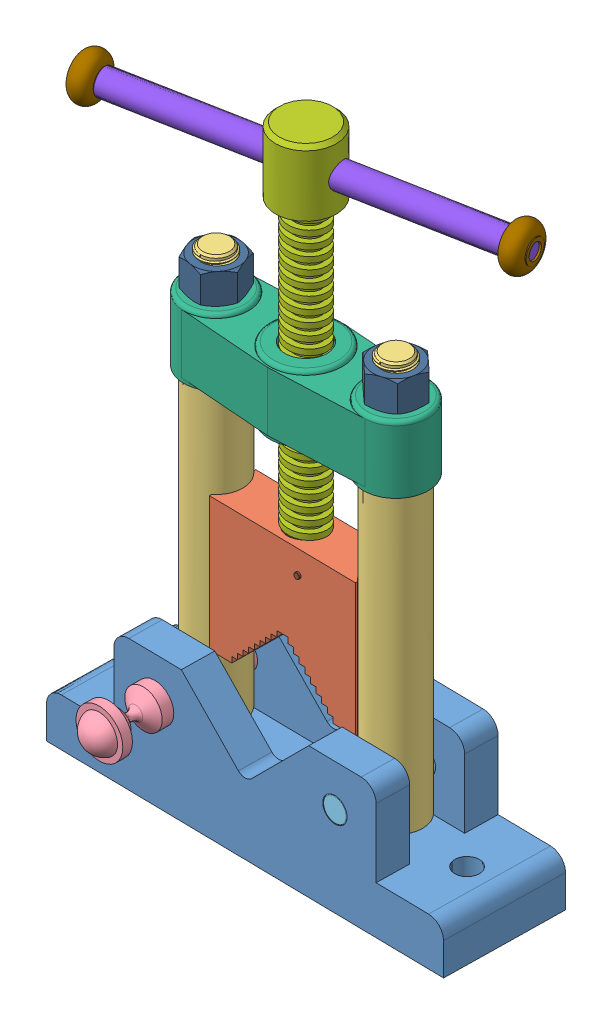
SolidWorks assembly Assem, configuration Default. Lengths in mm.
Overall size (213.02 319.89 110.24).
15 component instances, 11 part files, 36 mates.
Components (placement in the parent):
- Fixed jaw-1: Fixed jaw [Default] at (0.0506 112.578 -0.7967) x (0.999862 0 0.016599) z (-0.016599 0 0.999862) size (212 69 63)
- Movable jaw-1: Movable jaw [Default] at (-0.1493 248.4649 -0.8001) x (0.999862 0 0.016599) z (-0.016599 0 0.999862) size (78 70.54 24)
- Mounting shaft-1: Mounting shaft [Default] at (48.044 276.3556 0) x (0 1 0) z (-0.016599 0 0.999862) size (215.03 28 28)
- Mounting shaft-12: Mounting shaft [Default] at (-47.9428 276.3556 -1.5935) x (0 1 0) z (-0.016599 0 0.999862) size (215.03 28 28)
- Moving pin-1: Moving pin [Default] at (-48.3734 159.578 24.3472) x (0.016599 0 -0.999862) z (0.981424 -0.191161 0.016293) size (109.77 25 25)
- Mounting pin-1: Mounting pin [Default] at (48.5669 159.578 -31.4957) x (0.999862 0.000072 0.016599) z (0.000072 -1 0.000001) size (13 63 13)
- Connecting wedge-1: Connecting wedge [Default] at (0.0506 315.1075 -0.7967) x (0.999862 0 0.016599) z (-0.016599 0 0.999862) size (130 36.3 39.81)
- Spindle screw-1: Spindle screw [Default] at (0.0506 378.2572 -0.7967) x (0 -1 0) z (-0.982605 0 0.18571) size (214 32 32)
- Turning Shaft-1: Turning Shaft [Default] at (45.5082 414.4649 -9.3881) x (0.982605 0 -0.18571) z (0.17415 0.347303 0.92144) size (204 13 13)
- Knob-1: Knob [Default] at (-95.262 414.4649 17.2172) x (-0.129878 -0.71477 -0.687194) z (0.982605 0 -0.18571) size (23.16 23.16 12)
- Knob-2: Knob [Default] at (95.3633 414.4649 -18.8107) x (-0.161669 -0.492095 -0.855398) z (0.982605 0 -0.18571) size (23.16 23.16 12)
- hex nut gradec_iso-2: hex nut gradec_iso [ISO - 4034 - M16 - N] at (48.044 348.5075 0) x (-0.977063 0 -0.212949) z (0 1 0) size (24 27.71 15.9)
- hex nut gradec_iso-3: hex nut gradec_iso [ISO - 4034 - M16 - N] at (-47.9428 348.5075 -1.5935) x (0.938562 0 -0.345111) z (0 1 0) size (24 27.71 15.9)
- 7.3mm Pin-1: 7.3mm Pin [Default] at (8.3495 236.4649 -0.659) x (0.016599 0 -0.999862) z (0.091452 -0.995808 0.001518) size (26 3 3)
- hex nut gradec_iso-4: hex nut gradec_iso [ISO - 4034 - M6 - N] at (-47.4116 159.578 -33.5891) x (0.999862 0 0.016599) z (-0.016599 0 0.999862) size (10 11.55 6.1)
Mates (geometry in assembly coordinates):
- Concentric1: concentric anti-aligned: cylinder of Fixed jaw-1 through (47.8083 159.578 14.198) axis (-0.016599 0 0.999862) radius 6.5; cylinder of Mounting shaft-1 through (47.4963 159.578 32.9955) axis (0.016599 0 -0.999862) radius 6.525
- Width1: width: plane of Fixed jaw-1 through (-61.7051 173.578 -16.0239) normal (-0.016599 0 0.999862); plane of Fixed jaw-1 through (-62.1765 173.578 12.3722) normal (0.016599 0 -0.999862); cylinder of Mounting shaft-1 through (48.044 12.6842 0) axis (0 -1 0) radius 14
- Concentric8: concentric anti-aligned: cylinder of Mounting shaft-1 through (48.044 12.6842 0) axis (0 -1 0) radius 14
- Perpendicular1: perpendicular: plane of Fixed jaw-1 through (0.0506 137.578 -0.7967) normal (0 1 0)
- Concentric13: concentric anti-aligned: cylinder of Fixed jaw-1 through (-47.7071 159.578 -15.7915) axis (0.016599 0 -0.999862) radius 6.5; cylinder of Mounting shaft-9 through (-47.395 159.578 -34.5889) axis (-0.016599 0 0.999862) radius 6.525
- Width4: width: plane of Fixed jaw-1 through (-62.1765 173.578 12.3722) normal (0.016599 0 -0.999862); plane of Fixed jaw-1 through (-61.7051 173.578 -16.0239) normal (-0.016599 0 0.999862); cylinder of Mounting shaft-9 through (-20.4766 15.2755 -1.1375) axis (0.18698 -0.982359 0.003104) radius 14
- Concentric22: concentric anti-aligned: cylinder of Fixed jaw-1 through (-48.1785 159.578 12.6046) axis (-0.016599 0 0.999862) radius 6.5; cylinder of Mounting shaft-12 through (-48.4905 159.578 31.402) axis (0.016599 0 -0.999862) radius 6.525
- Width5: width: plane of Fixed jaw-1 through (-62.1765 173.578 12.3722) normal (0.016599 0 -0.999862); plane of Fixed jaw-1 through (-61.7051 173.578 -16.0239) normal (-0.016599 0 0.999862); cylinder of Mounting shaft-12 through (-47.9428 12.6842 -1.5935) axis (0 -1 0) radius 14
- Parallel6: parallel anti-aligned: cylinder of Mounting shaft-12 through (-47.9428 12.6842 -1.5935) axis (0 -1 0) radius 14
- Concentric27: concentric anti-aligned: cylinder of Movable jaw-1 through (-47.9428 178.4649 -1.5935) axis (0 1 0) radius 14; cylinder of Mounting shaft-12 through (-47.9428 12.6842 -1.5935) axis (0 -1 0) radius 14
- Width6: width: plane of Movable jaw-1 through (-0.3485 178.4649 11.1983) normal (-0.016599 0 0.999862); plane of Movable jaw-1 through (0.0498 178.4649 -12.7984) normal (0.016599 0 -0.999862); cylinder of Mounting shaft-1 through (48.044 12.6842 0) axis (0 -1 0) radius 14
- Concentric30: concentric aligned: cylinder of Fixed jaw-1 through (-48.1785 159.578 12.6046) axis (-0.016599 0 0.999862) radius 6.5; cylinder of Moving pin-1 through (-49.2355 159.578 76.2781) axis (-0.016599 0 0.999862) radius 7.5
- Coincident20: coincident anti-aligned: plane of Fixed jaw-1 through (-106.4576 137.578 28.9394) normal (-0.016599 0 0.999862); plane of Moving pin-1 through (-46.5543 169.3936 29.9339) normal (0.016599 0 -0.999862)
- Concentric31: concentric anti-aligned: cylinder of Fixed jaw-1 through (47.8083 159.578 14.198) axis (-0.016599 0 0.999862) radius 6.5; cylinder of Mounting pin-1 through (47.5212 159.578 31.4957) axis (0.016599 0 -0.999862) radius 6.5
- Coincident21: coincident aligned: plane of Fixed jaw-1 through (-106.4576 137.578 28.9394) normal (-0.016599 0 0.999862); plane of Mounting pin-1 through (47.5212 159.578 31.4957) normal (-0.016599 0 0.999862)
- Concentric32: concentric aligned: cylinder of Mounting shaft-12 through (-47.9428 12.6842 -1.5935) axis (0 -1 0) radius 10; cylinder of Connecting wedge-1 through (-47.9428 332.6075 -1.5935) axis (0 -1 0) radius 11
- Coincident22: coincident anti-aligned: plane of Mounting shaft-12 through (-61.9408 297.6075 -1.8259) normal (0 1 0); plane of Connecting wedge-1 through (0.0506 297.6075 -0.7967) normal (0 -1 0)
- Concentric33: concentric aligned: cylinder of Mounting shaft-1 through (48.044 12.6842 0) axis (0 -1 0) radius 10; cylinder of Connecting wedge-1 through (48.044 332.6075 0) axis (0 -1 0) radius 11
- Concentric34: concentric anti-aligned: cylinder of Connecting wedge-1 through (0.0506 332.6075 -0.7967) axis (0 -1 0) radius 11; cylinder of Spindle screw-1 through (0.0506 453.2736 -0.7967) axis (0 1 0) radius 7.4317
- Concentric35: concentric anti-aligned: cylinder of Spindle screw-1 through (-38.2709 414.4649 6.446) axis (0.982605 0 -0.18571) radius 6.5; cylinder of Turning Shaft-1 through (-116.7484 414.4649 21.2781) axis (-0.982605 0 0.18571) radius 6.5
- Width7: width: plane of Turning Shaft-1 through (100.0183 418.2159 -21.1043) normal (0.982605 0 -0.18571); plane of Turning Shaft-1 through (-100.175 414.4649 18.1457) normal (-0.982605 0 0.18571); cylinder of Spindle screw-1 through (0.0506 453.2736 -0.7967) axis (0 1 0) radius 16
- Concentric36: concentric anti-aligned: cylinder of Turning Shaft-1 through (-116.7484 414.4649 21.2781) axis (-0.982605 0 0.18571) radius 4; cylinder of Knob-2 through (105.5483 414.4649 -20.7356) axis (0.982605 0 -0.18571) radius 4.05
- Coincident25: coincident anti-aligned: plane of Turning Shaft-1 through (89.0484 420.5603 -19.9146) normal (0.982605 0 -0.18571); plane of Knob-2 through (89.0975 417.9906 -19.6547) normal (-0.982605 0 0.18571)
- Concentric37: concentric anti-aligned: cylinder of Turning Shaft-1 through (-116.7484 414.4649 21.2781) axis (-0.982605 0 0.18571) radius 4; cylinder of Knob-1 through (-85.0769 414.4649 15.2922) axis (0.982605 0 -0.18571) radius 4.05
- Coincident26: coincident anti-aligned: plane of Turning Shaft-1 through (-89.6244 418.2159 14.7379) normal (-0.982605 0 0.18571); plane of Knob-1 through (-90.1628 418.661 11.8889) normal (0.982605 0 -0.18571)
- Concentric39: concentric anti-aligned: cylinder of Connecting wedge-1 through (48.044 332.6075 0) axis (0 -1 0) radius 11; cylinder of hex nut gradec_iso-2 through (48.044 323.4699 0) axis (0 1 0) radius 8
- Coincident28: coincident anti-aligned: plane of Connecting wedge-1 through (0.0506 332.6075 -0.7967) normal (0 1 0); plane of hex nut gradec_iso-2 through (45.0933 332.6075 13.5386) normal (0 -1 0)
- Concentric40: concentric anti-aligned: cylinder of Connecting wedge-1 through (-47.9428 332.6075 -1.5935) axis (0 -1 0) radius 11; cylinder of hex nut gradec_iso-3 through (-47.9428 323.4699 -1.5935) axis (0 1 0) radius 8
- Coincident29: coincident anti-aligned: plane of Connecting wedge-1 through (0.0506 332.6075 -0.7967) normal (0 1 0); plane of hex nut gradec_iso-3 through (-52.7248 332.6075 -14.5986) normal (0 -1 0)
- Screw1: screw = 6 mm anti-aligned: cylinder of Connecting wedge-1 through (0.0506 332.6075 -0.7967) axis (0 -1 0) radius 11; cylinder of Spindle screw-1 through (0.0506 453.2736 -0.7967) axis (0 1 0) radius 10.2295
- Coincident31: coincident anti-aligned: plane of Movable jaw-1 through (-0.1493 248.4649 -0.8001) normal (0 1 0); plane of Spindle screw-1 through (1.9504 248.4649 9.2548) normal (0 -1 0)
- LimitDistance3: limit distance = 51.1426 mm anti-aligned: plane of Movable jaw-1 through (-0.1493 248.4649 -0.8001) normal (0 1 0); plane of Connecting wedge-1 through (0.0506 299.6075 -0.7967) normal (0 -1 0)
- Concentric41: concentric anti-aligned: cylinder of Movable jaw-1 through (8.1503 236.4649 11.3394) axis (0.016599 0 -0.999862) radius 1.5; cylinder of 7.3mm Pin-1 through (8.5653 236.4649 -13.6572) axis (-0.016599 0 0.999862) radius 1.5
- Width9: width anti-aligned: plane of 7.3mm Pin-1 through (8.5653 236.4649 -13.6572) normal (0.016599 0 -0.999862); plane of 7.3mm Pin-1 through (8.1337 236.4649 12.3392) normal (-0.016599 0 0.999862); plane of Movable jaw-1 through (-0.3485 178.4649 11.1983) normal (-0.016599 0 0.999862); plane of Movable jaw-1 through (0.0498 178.4649 -12.7984) normal (0.016599 0 -0.999862)
- Concentric42: concentric aligned: circle of Moving pin-1; cylinder of hex nut gradec_iso-4 through (-47.3103 159.578 -39.6882) axis (-0.016599 0 0.999862) radius 2.5
- Coincident33: coincident anti-aligned: plane of Moving pin-1 through (-45.9781 166.9397 -33.5653) normal (0.016599 0 -0.999862); plane of hex nut gradec_iso-4 through (-47.4116 165.3515 -33.5891) normal (-0.016599 0 0.999862)
